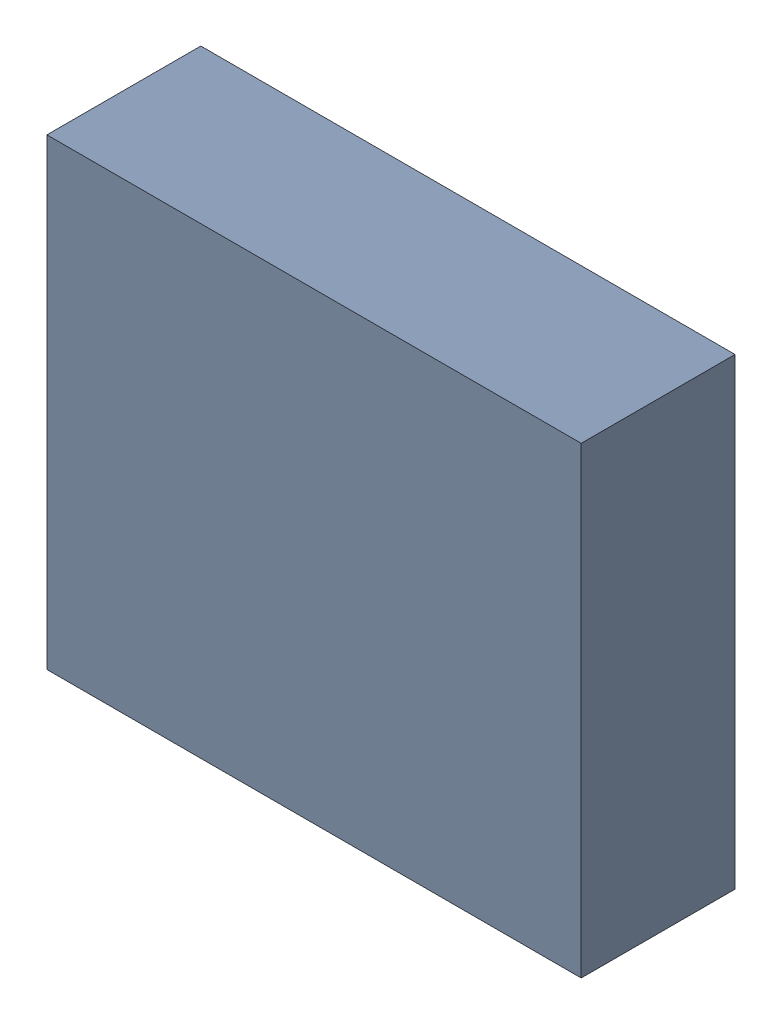
SolidWorks assembly SUDZOR2Kanaloa_v2.0.0_Power, configuration Default. Lengths in mm.
Overall size (7.5 6.5 2.16).
2 component instances, 1 part files, 0 mates.
Components (placement in the parent):
- 425993600-1: 425993600 [Default] at (104.125 37.65 -3.3124) size (7.5 6.5 2.16)
  - Extruded_7-1: Extruded_7 [Default] at origin size (7.5 6.5 2.16)
